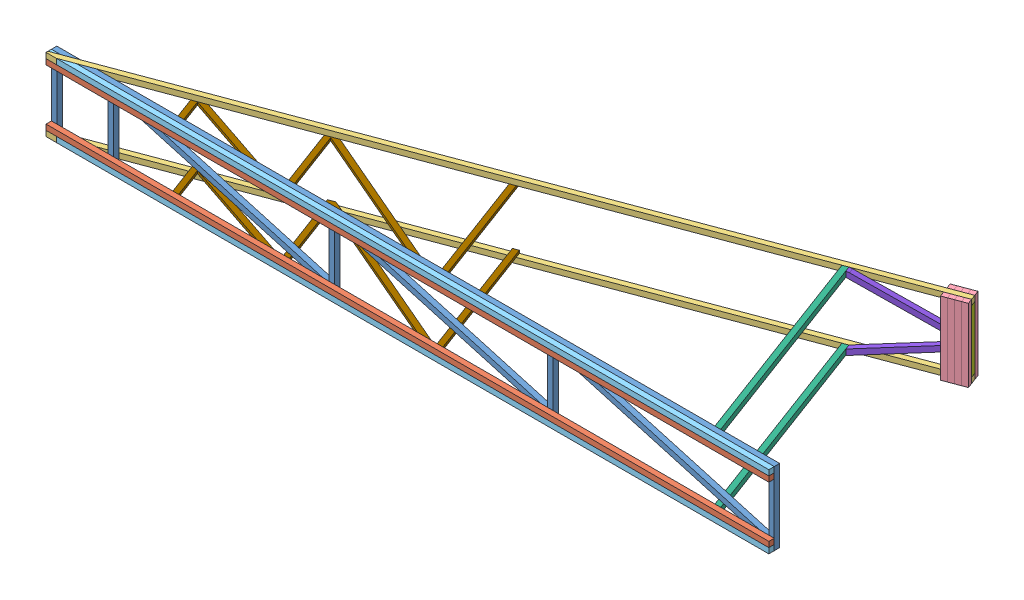
SolidWorks assembly boomAssembly3_2, configuration Default. Lengths in mm.
Overall size (423.17 42.7 151.68).
24 component instances, 10 part files, 100 mates.
Components (placement in the parent):
- cross brace compressionnew-1: cross brace compressionnew [Default] at (-109.2004 207.2528 347.8228) size (423.18 42.7 3.17)
- Part1-1: Part1 [Default] at (-109.2004 207.2528 354.1728) size (423.18 36.35 3.17)
- tension members-3: tension members [Default] at (269.1249 227.7278 350.9978) x (-1 0 0) z (0 0 1) size (396.18 3.18 148.71)
- tension members-4: tension members [Default] at (269.1249 267.2528 350.9978) x (-1 0 0) z (0 0 1) size (396.18 3.18 148.71)
- jHookMount-1: jHookMount [Default] at (264.7186 215.9028 209.7497) x (0.936777 0 -0.349926) z (0 1 0) size (3.17 3.17 42.7)
- jHookMount-2: jHookMount [Default] at (266.9407 215.9028 215.6982) x (0.936777 0 -0.349926) z (0 1 0) size (3.17 3.17 42.7)
- Part1^boomAssembly3_2-1: Part1^boomAssembly3_2 [Default] at origin (virtual)
- Part2^boomAssembly3_2-1: Part2^boomAssembly3_2 [Default] at (269.1249 258.6028 350.9978) x (1 0 0) z (0 1 0) size (423.17 3.17 3.17) (virtual)
- Part4^boomAssembly3_2-1: Part4^boomAssembly3_2 [Default] at (269.1249 258.6028 350.9978) x (1 0 0) z (0 1 0) size (47.74 119.85 3.17) (virtual)
- Part2^boomAssembly3_2-2: Part2^boomAssembly3_2 [Default] at (269.1249 219.0778 350.9978) x (1 0 0) z (0 1 0) size (423.17 3.17 3.17) (virtual)
- Part4^boomAssembly3_2-2: Part4^boomAssembly3_2 [Default] at (269.1249 219.0778 350.9978) x (1 0 0) z (0 1 0) size (47.74 119.85 3.17) (virtual)
- jHookMount-8: jHookMount [Default] at (261.7444 215.9028 210.8607) x (0.936777 0 -0.349926) z (0 1 0) size (3.17 3.17 42.7)
- jHookMount-9: jHookMount [Default] at (265.8296 215.9028 212.724) x (-0.936777 0 0.349926) z (0 1 0) size (3.17 3.17 42.7)
- jHookMount-10: jHookMount [Default] at (258.7701 215.9028 211.9717) x (0.936777 0 -0.349926) z (0 1 0) size (3.17 3.17 42.7)
- jHookMount-11: jHookMount [Default] at (260.9921 215.9028 217.9203) x (0.936777 0 -0.349926) z (0 1 0) size (3.17 3.17 42.7)
- Part5^boomAssembly3_2-1: Part5^boomAssembly3_2 [Default] at (267.6929 215.9028 208.6387) x (0 -1 0) z (0.936777 0 -0.349926) size (36.35 3.17 3.17) (virtual)
- Part5^boomAssembly3_2-2: Part5^boomAssembly3_2 [Default] at (264.7186 215.9028 209.7497) x (0 -1 0) z (0.936777 0 -0.349926) size (36.35 3.17 3.17) (virtual)
- Part5^boomAssembly3_2-3: Part5^boomAssembly3_2 [Default] at (261.7444 215.9028 210.8607) x (0 -1 0) z (0.936777 0 -0.349926) size (36.35 3.17 3.17) (virtual)
- jHookMount-16: jHookMount [Default] at (258.0179 215.9028 219.0313) x (0.936777 0 -0.349926) z (0 1 0) size (3.17 3.17 42.7)
- jHookMount-17: jHookMount [Default] at (255.7958 215.9028 213.0827) x (0.936777 0 -0.349926) z (0 1 0) size (3.17 3.17 42.7)
- Part9^boomAssembly3_2-1: Part9^boomAssembly3_2 [Default] at (223.3948 267.2528 228.5752) x (-0.936777 0 0.349926) z (0.349926 0 0.936777) size (43.12 42.7 3.17) (virtual)
- Part5^boomAssembly3_2-5: Part5^boomAssembly3_2 [Default] at (258.7701 215.9028 211.9717) x (0 -1 0) z (0.936777 0 -0.349926) size (36.35 3.17 3.17) (virtual)
- Part3^boomAssembly3_2-1: Part3^boomAssembly3_2 [Default] at (-109.2004 255.4278 347.8228) x (-1 0 0) z (0 -1 0) size (167.23 76.2 1.59) (virtual)
- Part3^boomAssembly3_2-2: Part3^boomAssembly3_2 [Default] at (-109.2004 220.6653 347.8228) x (-1 0 0) z (0 -1 0) size (167.23 76.2 1.59) (virtual)
Mates (geometry in assembly coordinates):
- Coincident4: coincident: plane of cross brace compressionnew-1 through (-127.3754 207.2528 350.9978) normal (-1 0 0); plane of Part1-1 through (-127.3754 207.2528 357.3478) normal (-1 0 0)
- Coincident5: coincident: plane of cross brace compressionnew-1 through (-109.2004 207.2528 354.1728) normal (0 0 1); plane of Part1-1 through (-109.2004 207.2528 354.1728) normal (0 0 -1)
- Coincident7: coincident: plane of Part1-1 through (-109.2004 207.2528 357.3478) normal (0 0 1); plane of tension members-3 through (291.79 227.7278 357.3478) normal (0 0 1)
- Coincident8: coincident: plane of cross brace compressionnew-1 through (-107.5644 219.0778 352.2026) normal (-0.349926 0 -0.936777); plane of tension members-3 through (223.3948 176.3778 228.5752) normal (0.349926 0 0.936777)
- Coincident9: coincident: plane of Part1-1 through (-109.2004 219.0778 357.3478) normal (0 -1 0); plane of tension members-3 through (291.79 219.0778 350.9978) normal (0 1 0)
- Coincident10: coincident: plane of cross brace compressionnew-1 through (-108.6754 255.4278 349.2284) normal (0.349926 0 0.936777); plane of tension members-4 through (222.2837 215.9028 225.6009) normal (-0.349926 0 -0.936777)
- Coincident11: coincident: plane of Part1-1 through (-109.2004 207.2528 357.3478) normal (0 0 1); plane of tension members-4 through (291.79 267.2528 357.3478) normal (0 0 1)
- Coincident12: coincident: plane of cross brace compressionnew-1 through (-131.8656 258.6028 347.8228) normal (0 1 0); plane of tension members-4 through (291.79 258.6028 350.9978) normal (0 1 0)
- Coincident13: coincident: plane of cross brace compressionnew-1 through (-131.8656 219.0778 347.8228) normal (0 1 0); plane of Part1-1 through (-109.2004 219.0778 357.3478) normal (0 -1 0)
- Coincident14: coincident: plane of tension members-3 through (222.2837 176.3778 225.6009) normal (-0.349926 0 -0.936777); plane of jHookMount-1 through (264.7186 258.6028 209.7497) normal (0.349926 0 0.936777)
- Coincident15: coincident: plane of tension members-4 through (291.79 258.6028 350.9978) normal (0 1 0); plane of jHookMount-1 through (264.7186 258.6028 209.7497) normal (0 1 0)
- Coincident17: coincident: plane of tension members-3 through (223.3948 176.3778 228.5752) normal (0.349926 0 0.936777); plane of jHookMount-2 through (265.8296 258.6028 212.724) normal (-0.349926 0 -0.936777)
- Coincident19: coincident: plane of tension members-3 through (291.79 215.9028 350.9978) normal (0 -1 0); plane of jHookMount-2 through (266.9407 215.9028 215.6982) normal (0 -1 0)
- InPlace1: in place: plane of tension members-4 through (291.79 258.6028 350.9978) normal (0 1 0); plane of ? through (0 258.6028 0) normal (0 1 0); moOrthogonalPlaneRef_w of tension members-4 through (291.79 258.6028 350.9978) normal (0 1 0); plane of ? through (0 258.6028 0) normal (0 0 -1); plane of tension members-4 through (291.79 258.6028 350.9978) normal (0 1 0); plane of ? through (0 258.6028 0) normal (1 0 0); plane of tension members-4 through (291.79 258.6028 350.9978) normal (0 1 0); unknown of ?
- Coincident20: coincident: plane of tension members-4; plane of Part2^boomAssembly3_2-1
- Coincident21: coincident: moOrthogonalPlaneRef_w of tension members-4 through (269.1249 258.6028 350.9978) normal (0 0 -1); plane of Part2^boomAssembly3_2-1 through (269.1249 258.6028 350.9978) normal (0 0 -1)
- Coincident22: coincident: moOrthogonalPlaneRef_w of tension members-4 through (269.1249 258.6028 350.9978) normal (-1 0 0); plane of Part2^boomAssembly3_2-1 through (269.1249 258.6028 350.9978) normal (1 0 0)
- Coincident23: coincident: plane of Part1-1 through (-109.2004 222.2528 357.3478) normal (0 1 0); plane of ? through (-109.2004 222.2528 360.5228) normal (0 1 0)
- Coincident24: coincident: plane of Part1-1 through (-109.2004 207.2528 357.3478) normal (0 0 1); plane of ? through (-109.2004 207.2528 357.3478) normal (0 0 -1)
- Coincident25: coincident: plane of cross brace compressionnew-1 through (-127.3754 207.2528 350.9978) normal (-1 0 0); plane of ? through (-127.3754 207.2528 360.5228) normal (-1 0 0)
- InPlace2: in place: plane of ? through (-127.3754 207.2528 360.5228) normal (-1 0 0); plane of ? through (-127.3754 0 0) normal (-1 0 0); plane of ? through (-127.3754 207.2528 360.5228) normal (-1 0 0); plane of ? through (-127.3754 0 0) normal (0 1 0); plane of ? through (-127.3754 207.2528 360.5228) normal (-1 0 0); plane of ? through (-127.3754 0 0) normal (0 0 1); plane of ? through (-127.3754 207.2528 360.5228) normal (-1 0 0); unknown of ?
- Coincident26: coincident: plane of ?; plane of ?
- Coincident27: coincident: moOrthogonalPlaneRef_w of ? through (-127.3754 207.2528 357.3478) normal (0 1 0); plane of ? through (-127.3754 207.2528 357.3478) normal (0 1 0)
- Coincident28: coincident: moOrthogonalPlaneRef_w of ? through (-127.3754 207.2528 357.3478) normal (0 0 -1); plane of ? through (-127.3754 207.2528 357.3478) normal (0 0 1)
- InPlace3: in place: plane of tension members-4 through (291.79 258.6028 350.9978) normal (0 1 0); plane of ? through (0 258.6028 0) normal (0 1 0); plane of tension members-4 through (291.79 258.6028 350.9978) normal (0 1 0); plane of ? through (0 258.6028 0) normal (0 0 -1); plane of tension members-4 through (291.79 258.6028 350.9978) normal (0 1 0); plane of ? through (0 258.6028 0) normal (1 0 0); plane of tension members-4 through (291.79 258.6028 350.9978) normal (0 1 0); unknown of ?
- Coincident29: coincident: plane of tension members-4; plane of Part4^boomAssembly3_2-1
- Coincident30: coincident: moOrthogonalPlaneRef_w of tension members-4 through (269.1249 258.6028 350.9978) normal (0 0 -1); plane of Part4^boomAssembly3_2-1 through (269.1249 258.6028 350.9978) normal (0 0 -1)
- Coincident31: coincident: moOrthogonalPlaneRef_w of tension members-4 through (269.1249 258.6028 350.9978) normal (-1 0 0); plane of Part4^boomAssembly3_2-1 through (269.1249 258.6028 350.9978) normal (1 0 0)
- Coincident32: coincident: plane of tension members-4 through (314.534 267.2528 334.0356) normal (0.936777 0 -0.349926); plane of jHookMount-1 through (267.6929 258.6028 208.6387) normal (0.936777 0 -0.349926)
- Coincident33: coincident: plane of tension members-4 through (314.534 267.2528 334.0356) normal (0.936777 0 -0.349926); plane of jHookMount-2 through (269.9149 258.6028 214.5872) normal (0.936777 0 -0.349926)
- Coincident34: coincident: plane of tension members-4 through (223.3948 215.9028 228.5752) normal (0.349926 0 0.936777); plane of jHookMount-11 through (259.8811 258.6028 214.946) normal (-0.349926 0 -0.936777)
- Coincident35: coincident: plane of tension members-4 through (223.3948 215.9028 228.5752) normal (0.349926 0 0.936777); plane of jHookMount-9 through (265.8296 258.6028 212.724) normal (-0.349926 0 -0.936777)
- Coincident36: coincident: plane of tension members-3 through (291.79 215.9028 350.9978) normal (0 -1 0); plane of jHookMount-9 through (265.8296 215.9028 212.724) normal (0 -1 0)
- Coincident37: coincident: plane of tension members-3 through (291.79 215.9028 350.9978) normal (0 -1 0); plane of jHookMount-11 through (260.9921 215.9028 217.9203) normal (0 -1 0)
- Coincident38: coincident: plane of tension members-3 through (222.2837 176.3778 225.6009) normal (-0.349926 0 -0.936777); plane of jHookMount-8 through (261.7444 258.6028 210.8607) normal (0.349926 0 0.936777)
- Coincident39: coincident: plane of tension members-3 through (222.2837 176.3778 225.6009) normal (-0.349926 0 -0.936777); plane of jHookMount-10 through (258.7701 258.6028 211.9717) normal (0.349926 0 0.936777)
- Coincident40: coincident: plane of tension members-3 through (291.79 215.9028 350.9978) normal (0 -1 0); plane of jHookMount-8 through (261.7444 215.9028 210.8607) normal (0 -1 0)
- Coincident41: coincident: plane of tension members-3 through (291.79 215.9028 350.9978) normal (0 -1 0); plane of jHookMount-10 through (258.7701 215.9028 211.9717) normal (0 -1 0)
- Coincident42: coincident: plane of jHookMount-1 through (264.7186 258.6028 209.7497) normal (-0.936777 0 0.349926); plane of jHookMount-8 through (264.7186 258.6028 209.7497) normal (0.936777 0 -0.349926)
- Coincident43: coincident: plane of jHookMount-8 through (261.7444 258.6028 210.8607) normal (-0.936777 0 0.349926); plane of jHookMount-10 through (261.7444 258.6028 210.8607) normal (0.936777 0 -0.349926)
- Coincident44: coincident: plane of jHookMount-2 through (266.9407 258.6028 215.6982) normal (-0.936777 0 0.349926); plane of jHookMount-9 through (265.8296 258.6028 212.724) normal (0.936777 0 -0.349926)
- Coincident45: coincident: plane of jHookMount-9 through (262.8554 258.6028 213.835) normal (-0.936777 0 0.349926); plane of jHookMount-11 through (263.9664 258.6028 216.8092) normal (0.936777 0 -0.349926)
- InPlace4: in place: plane of jHookMount-8 through (264.7186 258.6028 209.7497) normal (0.936777 0 -0.349926); plane of ? through (163.5476 0 -61.092) normal (0.936777 0 -0.349926); plane of jHookMount-8 through (264.7186 258.6028 209.7497) normal (0.936777 0 -0.349926); plane of ? through (163.5476 0 -61.092) normal (0 1 0); plane of jHookMount-8 through (264.7186 258.6028 209.7497) normal (0.936777 0 -0.349926); plane of ? through (163.5476 0 -61.092) normal (-0.349926 0 -0.936777); plane of jHookMount-1 through (267.6929 258.6028 208.6387) normal (0.936777 0 -0.349926); unknown of Part5^boomAssembly3_2-1
- Coincident46: coincident: plane of jHookMount-1; plane of Part5^boomAssembly3_2-1
- Coincident47: coincident: moOrthogonalPlaneRef_w of jHookMount-1 through (267.6929 215.9028 208.6387) normal (-0.349926 0 -0.936777); plane of Part5^boomAssembly3_2-1 through (267.6929 215.9028 208.6387) normal (-0.349926 0 -0.936777)
- Coincident48: coincident: moOrthogonalPlaneRef_w of jHookMount-1 through (267.6929 215.9028 208.6387) normal (0 1 0); plane of Part5^boomAssembly3_2-1 through (267.6929 215.9028 208.6387) normal (0 -1 0)
- Coincident49: coincident: plane of tension members-4 through (291.79 255.4278 350.9978) normal (0 -1 0); plane of Part5^boomAssembly3_2-2 through (261.7444 255.4278 210.8607) normal (0 1 0)
- Coincident50: coincident: plane of Part5^boomAssembly3_2-1 through (264.7186 215.9028 209.7497) normal (-0.936777 0 0.349926); plane of Part5^boomAssembly3_2-2 through (264.7186 215.9028 209.7497) normal (0.936777 0 -0.349926)
- Coincident51: coincident: plane of jHookMount-8 through (261.7444 258.6028 210.8607) normal (0.349926 0 0.936777); plane of Part5^boomAssembly3_2-2 through (261.7444 255.4278 210.8607) normal (-0.349926 0 -0.936777)
- Coincident52: coincident: plane of jHookMount-10 through (258.7701 258.6028 211.9717) normal (0.349926 0 0.936777); plane of Part5^boomAssembly3_2-3 through (258.7701 255.4278 211.9717) normal (-0.349926 0 -0.936777)
- Coincident53: coincident: plane of tension members-4 through (291.79 255.4278 350.9978) normal (0 -1 0); plane of Part5^boomAssembly3_2-3 through (258.7701 255.4278 211.9717) normal (0 1 0)
- Coincident54: coincident: plane of Part5^boomAssembly3_2-2 through (261.7444 215.9028 210.8607) normal (-0.936777 0 0.349926); plane of Part5^boomAssembly3_2-3 through (261.7444 215.9028 210.8607) normal (0.936777 0 -0.349926)
- Coincident55: coincident: plane of jHookMount-2 through (266.9407 258.6028 215.6982) normal (0.936777 0 -0.349926); plane of ? through (265.8296 212.7278 212.724) normal (-0.936777 0 0.349926)
- Coincident56: coincident: plane of tension members-3 through (223.3948 176.3778 228.5752) normal (0.349926 0 0.936777); plane of ? through (265.8296 252.2528 212.724) normal (-0.349926 0 -0.936777)
- Coincident57: coincident: plane of jHookMount-2 through (263.9664 215.9028 216.8092) normal (0 -1 0); plane of ? through (265.8296 215.9028 212.724) normal (0 -1 0)
- Coincident58: coincident: plane of Part5^boomAssembly3_2-1 through (267.6929 215.9028 208.6387) normal (0.936777 0 -0.349926); plane of ? through (267.6929 215.9028 208.6387) normal (-0.936777 0 0.349926)
- Coincident59: coincident: plane of tension members-3 through (291.79 219.0778 350.9978) normal (0 1 0); plane of ? through (267.6929 219.0778 208.6387) normal (0 -1 0)
- Coincident60: coincident: plane of tension members-3 through (222.2837 176.3778 225.6009) normal (-0.349926 0 -0.936777); plane of ? through (267.6929 255.4278 208.6387) normal (-0.349926 0 -0.936777)
- Coincident61: coincident: plane of tension members-3 through (291.79 215.9028 350.9978) normal (0 -1 0); plane of ? through (268.8039 215.9028 211.6129) normal (0 -1 0)
- Coincident62: coincident: plane of Part5^boomAssembly3_2-1 through (267.6929 215.9028 208.6387) normal (0.936777 0 -0.349926); plane of ? through (268.8039 258.6028 211.6129) normal (-0.936777 0 0.349926)
- Coincident63: coincident: plane of tension members-3 through (222.2837 176.3778 225.6009) normal (-0.349926 0 -0.936777); plane of ? through (267.6929 258.6028 208.6387) normal (-0.349926 0 -0.936777)
- Coincident64: coincident: plane of ? through (271.7782 258.6028 210.5019) normal (0.936777 0 -0.349926); plane of ? through (270.6672 258.6028 207.5277) normal (0.936777 0 -0.349926)
- Coincident65: coincident: plane of ? through (271.7782 258.6028 210.5019) normal (0.936777 0 -0.349926); plane of ? through (272.8862 258.6028 213.4681) normal (0.936777 0 -0.349926)
- Coincident66: coincident: plane of ? through (268.8039 215.9028 211.6129) normal (0 -1 0); plane of ? through (267.6929 215.9028 208.6387) normal (0 -1 0)
- Coincident67: coincident: plane of ? through (268.8039 215.9028 211.6129) normal (0 -1 0); plane of ? through (269.9119 215.9028 214.5791) normal (0 -1 0)
- Coincident68: coincident: plane of ? through (267.6929 258.6028 208.6387) normal (-0.349926 0 -0.936777); plane of ? through (267.6929 258.6028 208.6387) normal (0.349926 0 0.936777)
- InPlace5: in place: plane of tension members-3 through (222.2837 176.3778 225.6009) normal (-0.349926 0 -0.936777); plane of ? through (101.171 0 270.8417) normal (-0.349926 0 -0.936777); plane of tension members-3 through (222.2837 176.3778 225.6009) normal (-0.349926 0 -0.936777); plane of ? through (101.171 0 270.8417) normal (0 1 0); plane of tension members-3 through (222.2837 176.3778 225.6009) normal (-0.349926 0 -0.936777); plane of ? through (101.171 0 270.8417) normal (-0.936777 0 0.349926); plane of tension members-3 through (222.2837 176.3778 225.6009) normal (-0.349926 0 -0.936777); unknown of ?
- Coincident69: coincident: plane of tension members-3; plane of ?
- Coincident70: coincident: moOrthogonalPlaneRef_w of tension members-3 through (222.2837 227.7278 225.6009) normal (0 -1 0); plane of ? through (222.2837 227.7278 225.6009) normal (0 -1 0)
- Coincident71: coincident: moOrthogonalPlaneRef_w of tension members-3 through (222.2837 227.7278 225.6009) normal (-0.936777 0 0.349926); plane of ? through (222.2837 227.7278 225.6009) normal (0.936777 0 -0.349926)
- Coincident72: coincident: plane of ? through (223.3948 215.9028 228.5752) normal (0.349926 0 0.936777); plane of jHookMount-16 through (256.9068 258.6028 216.057) normal (-0.349926 0 -0.936777)
- Coincident73: coincident: plane of tension members-3 through (222.2837 176.3778 225.6009) normal (-0.349926 0 -0.936777); plane of jHookMount-17 through (255.7958 258.6028 213.0827) normal (0.349926 0 0.936777)
- Coincident74: coincident: plane of jHookMount-11 through (260.9921 215.9028 217.9203) normal (0 -1 0); plane of jHookMount-16 through (258.0179 215.9028 219.0313) normal (0 -1 0)
- Coincident75: coincident: plane of tension members-3 through (291.79 215.9028 350.9978) normal (0 -1 0); plane of jHookMount-17 through (255.7958 215.9028 213.0827) normal (0 -1 0)
- Coincident76: coincident: plane of jHookMount-10 through (258.7701 258.6028 211.9717) normal (-0.936777 0 0.349926); plane of jHookMount-17 through (258.7701 258.6028 211.9717) normal (0.936777 0 -0.349926)
- Coincident77: coincident: plane of jHookMount-11 through (260.9921 258.6028 217.9203) normal (-0.936777 0 0.349926); plane of jHookMount-16 through (260.9921 258.6028 217.9203) normal (0.936777 0 -0.349926)
- InPlace6: in place: plane of tension members-3 through (222.2837 176.3778 225.6009) normal (-0.349926 0 -0.936777); plane of ? through (101.171 0 270.8417) normal (-0.349926 0 -0.936777); plane of tension members-3 through (222.2837 176.3778 225.6009) normal (-0.349926 0 -0.936777); plane of ? through (101.171 0 270.8417) normal (0 1 0); plane of tension members-3 through (222.2837 176.3778 225.6009) normal (-0.349926 0 -0.936777); plane of ? through (101.171 0 270.8417) normal (-0.936777 0 0.349926); plane of tension members-3 through (222.2837 176.3778 225.6009) normal (-0.349926 0 -0.936777); unknown of ?
- Coincident78: coincident: plane of tension members-3; plane of ?
- Coincident79: coincident: moOrthogonalPlaneRef_w of tension members-3 through (222.2837 227.7278 225.6009) normal (0 -1 0); plane of ? through (222.2837 227.7278 225.6009) normal (0 -1 0)
- Coincident80: coincident: moOrthogonalPlaneRef_w of tension members-3 through (222.2837 227.7278 225.6009) normal (-0.936777 0 0.349926); plane of ? through (222.2837 227.7278 225.6009) normal (0.936777 0 -0.349926)
- Coincident81: coincident: plane of jHookMount-16 through (258.0179 258.6028 219.0313) normal (-0.936777 0 0.349926); plane of ? through (256.9068 229.7528 216.057) normal (0.936777 0 -0.349926)
- Coincident82: coincident: plane of tension members-3 through (291.79 215.9028 350.9978) normal (0 -1 0); plane of ? through (233.0113 215.9028 224.983) normal (0 -1 0)
- Coincident83: coincident: plane of tension members-3 through (223.3948 176.3778 228.5752) normal (0.349926 0 0.936777); plane of ? through (223.3948 227.7278 228.5752) normal (-0.349926 0 -0.936777)
- InPlace7: in place: plane of tension members-4 through (223.3948 215.9028 228.5752) normal (0.349926 0 0.936777); plane of ? through (102.282 0 273.816) normal (0.349926 0 0.936777); plane of tension members-4 through (223.3948 215.9028 228.5752) normal (0.349926 0 0.936777); plane of ? through (102.282 0 273.816) normal (0 1 0); plane of tension members-4 through (223.3948 215.9028 228.5752) normal (0.349926 0 0.936777); plane of ? through (102.282 0 273.816) normal (0.936777 0 -0.349926); plane of tension members-4 through (223.3948 215.9028 228.5752) normal (0.349926 0 0.936777); unknown of Part9^boomAssembly3_2-1
- Coincident84: coincident: plane of tension members-4; plane of ?
- Coincident85: coincident: moOrthogonalPlaneRef_w of tension members-4 through (223.3948 267.2528 228.5752) normal (0 -1 0); plane of Part9^boomAssembly3_2-1 through (223.3948 267.2528 228.5752) normal (0 -1 0)
- Coincident86: coincident: moOrthogonalPlaneRef_w of tension members-4 through (223.3948 267.2528 228.5752) normal (0.936777 0 -0.349926); plane of Part9^boomAssembly3_2-1 through (223.3948 267.2528 228.5752) normal (-0.936777 0 0.349926)
- InPlace8: in place: plane of tension members-4 through (223.3948 215.9028 228.5752) normal (0.349926 0 0.936777); plane of ? through (102.282 0 273.816) normal (0.349926 0 0.936777); plane of tension members-4 through (223.3948 215.9028 228.5752) normal (0.349926 0 0.936777); plane of ? through (102.282 0 273.816) normal (0 1 0); plane of tension members-4 through (223.3948 215.9028 228.5752) normal (0.349926 0 0.936777); plane of ? through (102.282 0 273.816) normal (0.936777 0 -0.349926); plane of tension members-4 through (223.3948 215.9028 228.5752) normal (0.349926 0 0.936777); unknown of Part9^boomAssembly3_2-1
- Coincident87: coincident: plane of tension members-4; plane of Part9^boomAssembly3_2-1
- Coincident88: coincident: moOrthogonalPlaneRef_w of tension members-4 through (223.3948 267.2528 228.5752) normal (0 -1 0); plane of Part9^boomAssembly3_2-1 through (223.3948 267.2528 228.5752) normal (0 -1 0)
- Coincident89: coincident: moOrthogonalPlaneRef_w of tension members-4 through (223.3948 267.2528 228.5752) normal (0.936777 0 -0.349926); plane of Part9^boomAssembly3_2-1 through (223.3948 267.2528 228.5752) normal (-0.936777 0 0.349926)
- Coincident84: coincident: plane of tension members-4 through (291.79 255.4278 350.9978) normal (0 -1 0); plane of ? through (254.23 255.4278 217.0569) normal (0 1 0)
- Coincident85: coincident: plane of tension members-4 through (222.2837 215.9028 225.6009) normal (-0.349926 0 -0.936777); plane of ? through (253.119 255.4278 214.0826) normal (-0.349926 0 -0.936777)
- Coincident89: coincident: plane of tension members-4 through (291.79 255.4278 350.9978) normal (0 -1 0); plane of Part5^boomAssembly3_2-5 through (255.7958 255.4278 213.0827) normal (0 1 0)
- Coincident90: coincident: plane of tension members-4 through (222.2837 215.9028 225.6009) normal (-0.349926 0 -0.936777); plane of Part5^boomAssembly3_2-5 through (255.7958 255.4278 213.0827) normal (-0.349926 0 -0.936777)
- Coincident91: coincident: plane of Part5^boomAssembly3_2-3 through (258.7701 215.9028 211.9717) normal (-0.936777 0 0.349926); plane of Part5^boomAssembly3_2-5 through (258.7701 215.9028 211.9717) normal (0.936777 0 -0.349926)
- InPlace9: in place: plane of cross brace compressionnew-1 through (-109.2004 255.4278 354.1728) normal (0 -1 0); plane of ? through (0 255.4278 0) normal (0 -1 0); plane of cross brace compressionnew-1 through (-109.2004 255.4278 354.1728) normal (0 -1 0); plane of ? through (0 255.4278 0) normal (0 0 -1); plane of cross brace compressionnew-1 through (-109.2004 255.4278 354.1728) normal (0 -1 0); plane of ? through (0 255.4278 0) normal (-1 0 0); plane of cross brace compressionnew-1 through (-109.2004 255.4278 354.1728) normal (0 -1 0); unknown of Part3^boomAssembly3_2-1
- Coincident92: coincident: plane of cross brace compressionnew-1; plane of Part3^boomAssembly3_2-1
- Coincident93: coincident: moOrthogonalPlaneRef_w of cross brace compressionnew-1 through (-109.2004 255.4278 347.8228) normal (0 0 -1); plane of Part3^boomAssembly3_2-1 through (-109.2004 255.4278 347.8228) normal (0 0 -1)
- Coincident94: coincident: moOrthogonalPlaneRef_w of cross brace compressionnew-1 through (-109.2004 255.4278 347.8228) normal (1 0 0); plane of Part3^boomAssembly3_2-1 through (-109.2004 255.4278 347.8228) normal (-1 0 0)
